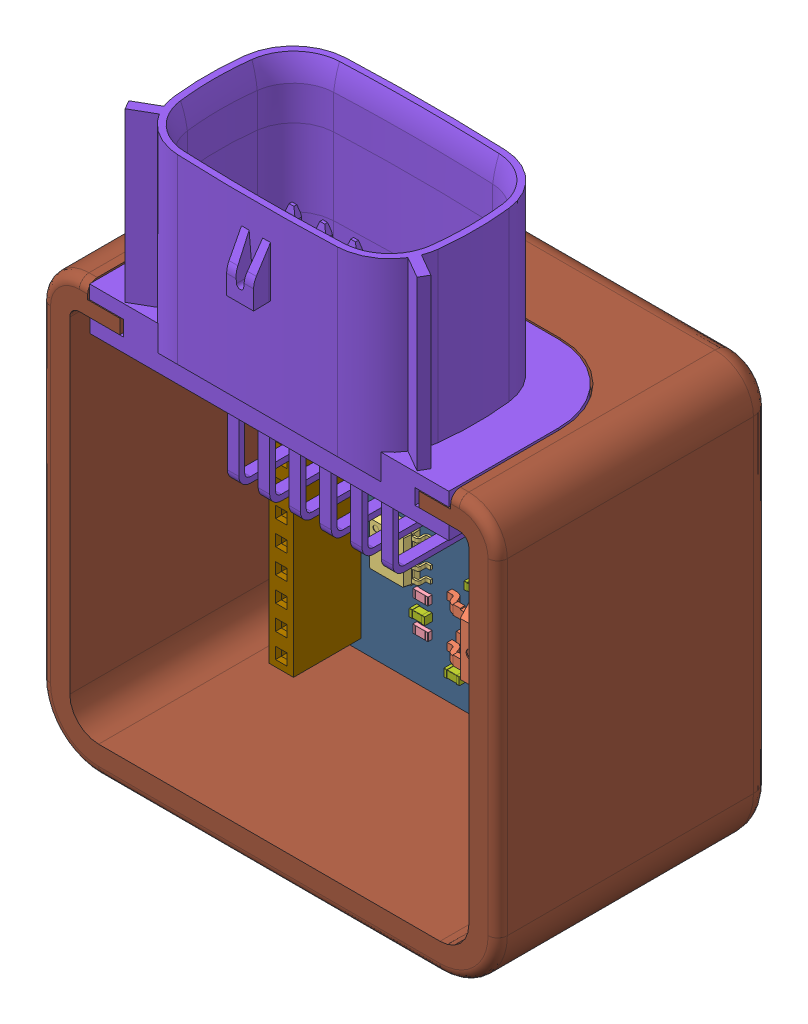
SolidWorks assembly board_carrier.step, configuration Default. Lengths in mm.
Overall size (47.5 61.42 31.65).
30 component instances, 11 part files, 1 mates.
Components (placement in the parent):
- C_0402_1005Metric.step-1: C_0402_1005Metric.step [Default] at (-7.7 -1.7 1.65) x (-1 0 0) z (0 0 1) size (1 0.5 0.5)
  - SOLID.step-1: SOLID.step [Default] at origin size (1 0.5 0.5)
- C_0402_1005Metric.step-2: C_0402_1005Metric.step [Default] at (-4.8 -2.9 1.65) x (-1 0 0) z (0 0 1) size (1 0.5 0.5)
  - SOLID.step-1: SOLID.step [Default] at origin size (1 0.5 0.5)
- TO-252-2.step-1: TO-252-2.step [Default] at (3 -10.5 1.65) size (9.9 6.5 2.32)
  - SOLID-0.step-1: SOLID-0.step [Default] at origin size (9.9 6.5 2.32)
- SOIC-8_3.9x4.9mm_P1.27mm.step-1: SOIC-8_3.9x4.9mm_P1.27mm.step [Default] at (-7 -6.25 1.65) size (6 4.9 1.75)
  - SOLID-1.step-1: SOLID-1.step [Default] at origin size (6 4.9 1.75)
- R_0603_1608Metric.step-1: R_0603_1608Metric.step [Default] at (-4.8 -9.8 1.65) x (-1 0 0) z (0 0 1) size (1.6 0.8 0.45)
  - SOLID-2.step-1: SOLID-2.step [Default] at origin size (1.6 0.8 0.45)
- R_0603_1608Metric.step-2: R_0603_1608Metric.step [Default] at (-4.8 -13 1.65) x (-1 0 0) z (0 0 1) size (1.6 0.8 0.45)
  - SOLID-2.step-1: SOLID-2.step [Default] at origin size (1.6 0.8 0.45)
- D_SMA.step-1: D_SMA.step [Default] at (-3.75 3.25 1.65) x (-1 0 0) z (0 0 1) size (5 2.7 2.22)
  - SOLID-3.step-1: SOLID-3.step [Default] at origin size (5 2.7 2.22)
- D_SMC.step-1: D_SMC.step [Default] at (7.1 -0.8 1.65) x (0 1 0) z (0 0 1) size (8 5.9 2.31)
  - SOLID-4.step-1: SOLID-4.step [Default] at origin size (8 5.9 2.31)
- C_0603_1608Metric.step-1: C_0603_1608Metric.step [Default] at (-4.8 -11.4 1.65) x (-1 0 0) z (0 0 1) size (1.6 0.8 0.8)
  - SOLID-5.step-1: SOLID-5.step [Default] at origin size (1.6 0.8 0.8)
- C_0603_1608Metric.step-2: C_0603_1608Metric.step [Default] at (-1.2 -15 1.65) size (1.6 0.8 0.8)
  - SOLID-5.step-1: SOLID-5.step [Default] at origin size (1.6 0.8 0.8)
- C_0603_1608Metric.step-3: C_0603_1608Metric.step [Default] at (0.9 -6.1 1.65) size (1.6 0.8 0.8)
  - SOLID-5.step-1: SOLID-5.step [Default] at origin size (1.6 0.8 0.8)
- 367831201.step-1: 367831201.step [Default] at (1.6 68.7 16.05) x (-1 0 0) z (0 0 -1) size (37.36 32.46 27.65)
  - COMPOUND.step-1: COMPOUND.step [Default] at origin size (37.36 32.46 27.65)
- PinSocket_1x08_P2.54mm_Vertical.step-1: PinSocket_1x08_P2.54mm_Vertical.step [Default] at (12.7 2 1.65) size (2.54 20.32 10.1)
  - SOLID-6.step-1: SOLID-6.step [Default] at origin size (2.54 20.32 10.1)
- PinSocket_1x08_P2.54mm_Vertical.step-2: PinSocket_1x08_P2.54mm_Vertical.step [Default] at (-12.7 2 1.65) size (2.54 20.32 10.1)
  - SOLID-6.step-1: SOLID-6.step [Default] at origin size (2.54 20.32 10.1)
- COMPOUND-7.step-1: COMPOUND-7.step [Default] at origin size (40 36.5 1.6)
- Part13^board_carrier.step-1: Part13^board_carrier.step [Default] at origin size (47.5 43.96 28.6) (virtual)
Mates (geometry in assembly coordinates):
- Coincident3: coordinate: point of assembly; point of Part13^board_carrier.step-1; point of assembly
